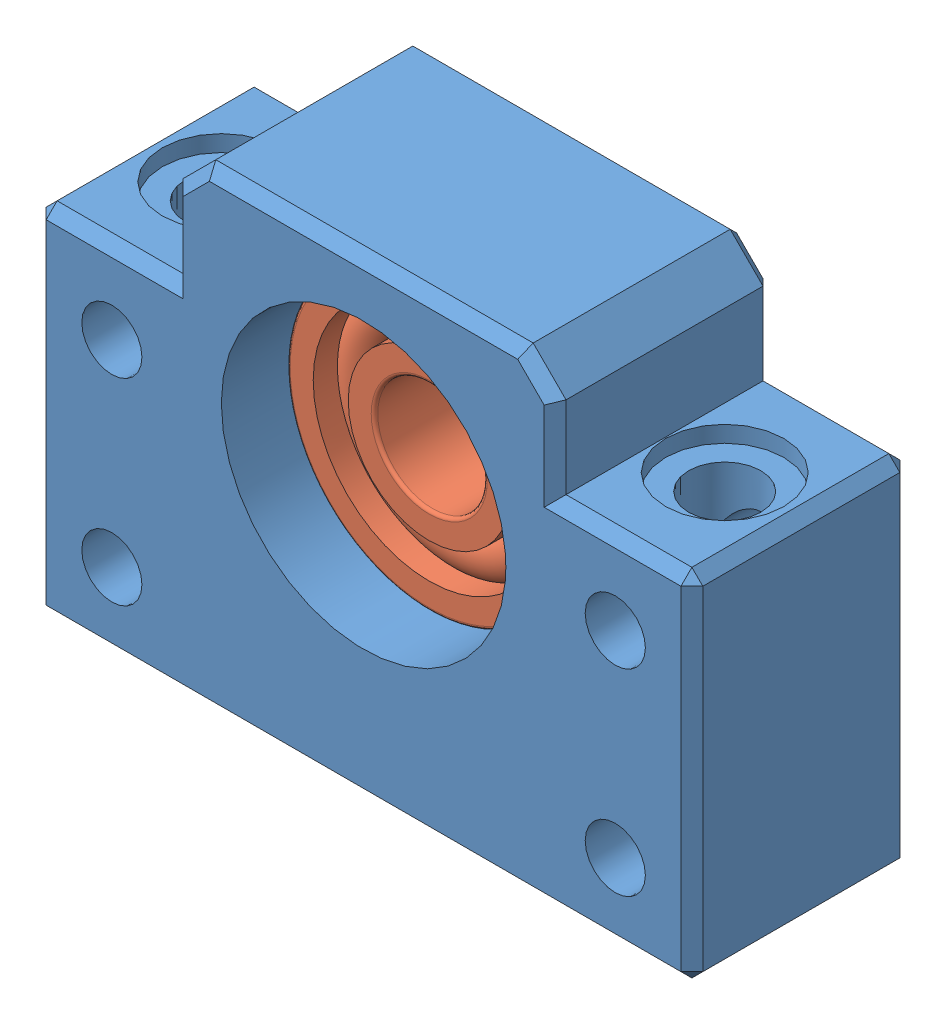
SolidWorks assembly BF12, configuration Valor predeterminado. Lengths in mm.
Overall size (60 43 20).
3 component instances, 3 part files, 4 mates.
Components (placement in the parent):
- BF12-Bloco-1: BF12-Bloco [Valor predeterminado] at (0.4341 3.1021 60) size (60 43 20)
- radial ball bearing_68_skf-1: radial ball bearing_68_skf [SKF - 6000 - 8,SI,NC,8_68] at (0.4341 3.1021 70) x (0 0 1) z (-1 0 0) size (8 26 26)
- gripring external retaining ring_wti-1: gripring external retaining ring_wti [Truarc 5555-37 - OS] at (0.4341 3.1021 66) x (0.998987 -0.04501 0) z (0 0 1) size (13.57 15.64 1.07)
Mates (geometry in assembly coordinates):
- Concêntrico1: concentric anti-aligned: cylinder of BF12-Bloco-1 through (0.4341 3.1021 80) axis (0 0 -1) radius 13; cylinder of radial ball bearing_68_skf-1 through (0.4341 3.1021 49.3625) axis (0 0 1) radius 13
- Largura1: width aligned: plane of radial ball bearing_68_skf-1 through (0.4341 15.8021 74) normal (0 0 1); plane of radial ball bearing_68_skf-1 through (0.4341 13.7021 66) normal (0 0 -1); plane of BF12-Bloco-1 through (0.4341 3.1021 80) normal (0 0 1); plane of BF12-Bloco-1 through (0.4341 3.1021 60) normal (0 0 -1)
- Concêntrico2: concentric aligned: cylinder of radial ball bearing_68_skf-1 through (0.4341 3.1021 49.3625) axis (0 0 1) radius 5; cylinder of gripring external retaining ring_wti-1 through (0.4341 3.1021 64.9332) axis (0 0 1) radius 4.7371
- Coincidente1: coincident anti-aligned: plane of radial ball bearing_68_skf-1 through (0.4341 10.5021 66) normal (0 0 -1); plane of gripring external retaining ring_wti-1 through (0.4341 3.1021 66) normal (0 0 1)
